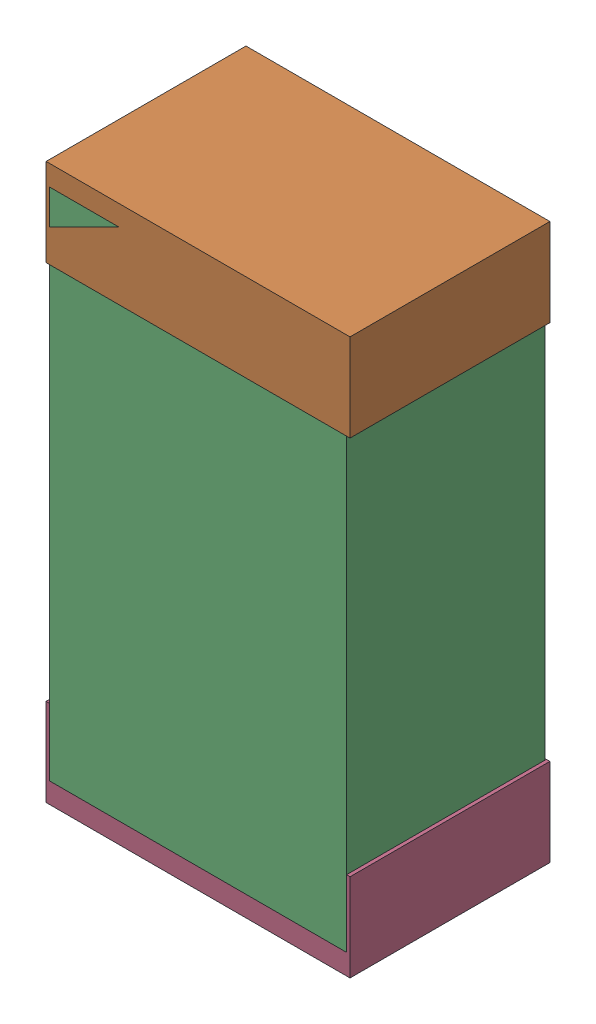
SolidWorks assembly Bat1StatKanaloa_v2.0.0_Power, configuration Default. Lengths in mm.
Overall size (1.3 2.38 0.87).
8 component instances, 3 part files, 0 mates.
Components (placement in the parent):
- 440440848-1: 440440848 [Default] at (123.275 38.2156 -1.9724) size (0.51 1.02 0.87)
  - Extruded_4-1: Extruded_4 [Default] at origin size (0.51 1.02 0.87)
- 330415056-1: 330415056 [Default] at (123.275 39.2156 -1.9574) size (1.3 0.38 0.85)
  - Extruded_2-1: Extruded_2 [Default] at origin size (1.3 0.38 0.85)
- 352877008-1: 352877008 [Default] at (123.275 38.2156 -1.9524) size (1.27 2.2 0.85)
  - Extruded_3-1: Extruded_3 [Default] at origin size (1.27 2.2 0.85)
- 330415056-2: 330415056 [Default] at (123.275 37.2156 -1.9574) size (1.3 0.38 0.85)
  - Extruded_2-1: Extruded_2 [Default] at origin size (1.3 0.38 0.85)
